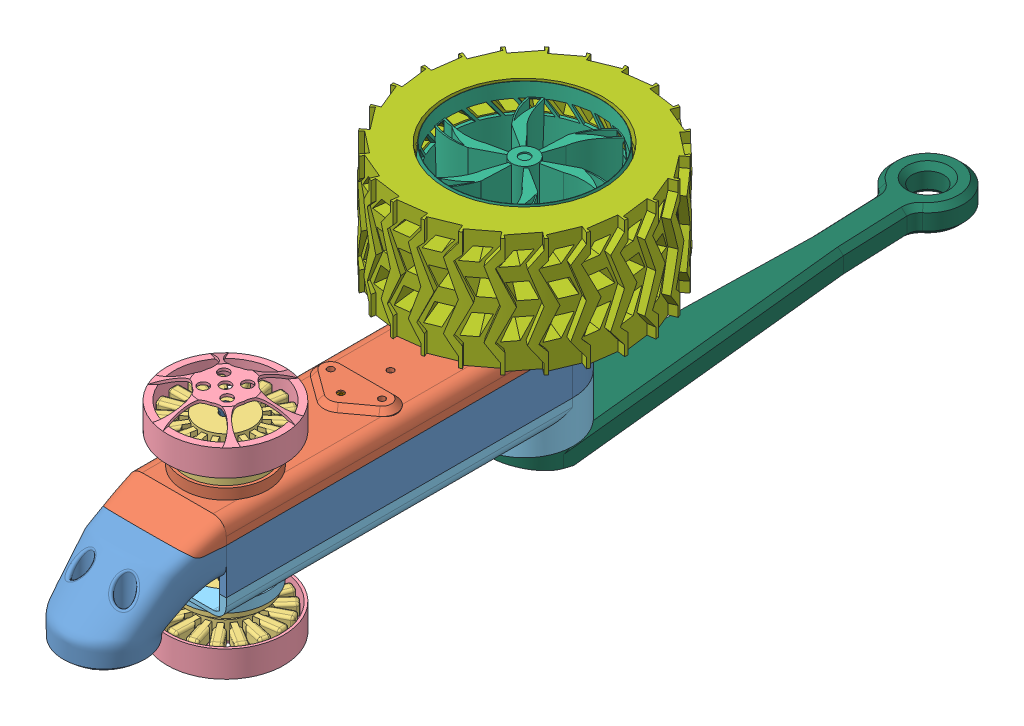
SolidWorks assembly actuator core v2, configuration Default. Lengths in mm.
Overall size (129.6 114.49 349.41).
35 component instances, 16 part files, 37 mates.
Components (placement in the parent):
- upper leg module shell base_v2-1: upper leg module shell base_v2 [Default] at (33.8696 112.35 155.1525) x (-1 0 0) z (0 0 -1) size (37.03 37.51 198.25)
- upper leg module cover_v2-1: upper leg module cover_v2 [Default] at (33.8696 118.35 148.7817) x (0 0 1) z (-1 0 0) size (170.23 17.96 37.06)
- T-motor 4004 kv300-1: T-motor 4004 kv300 [Default] at (68.2159 118.2197 199.3062) x (-0.164171 0 0.986432) z (-0.986432 0 -0.164171) size (60.94 23.74 60.94)
  - motor rotor-1: motor rotor [Default] at (14.1676 19.6303 32.4608) size (40 13.5 39.72)
  - motor stator-1: motor stator [Default] at (14.1676 19.6303 32.4608) x (0.854442 0 0.519546) z (0 1 0) size (44.35 44.35 16.24)
- upper leg module cover_v2_2-1: upper leg module cover_v2_2 [Default] at (33.8696 101.1 148.7817) x (0 0 1) z (1 0 0) size (150.55 16.02 37.05)
- T-motor 4004 kv300-2: T-motor 4004 kv300 [Default] at (54.5487 101.2303 179.1983) x (-0.977624 0 -0.21036) z (-0.21036 0 0.977624) size (60.94 23.74 60.94)
  - motor rotor-1: motor rotor [Default] at (14.1676 19.6303 32.4608) size (40 13.5 39.72)
  - motor stator-1: motor stator [Default] at (14.1676 19.6303 32.4608) x (0.854442 0 0.519546) z (0 1 0) size (44.35 44.35 16.24)
- Wheel assembly with motor-1: Wheel assembly with motor [Default] at (75.6805 196.4252 90.9747) x (-0.546944 0 0.837169) z (0 -1 0) size (125.19 125.19 45)
  - wheel-1: wheel [Default] at (25.5285 33.2647 43.0752) size (60 60 45) (hidden)
  - tyre-1: tyre [Default] at (25.5285 33.2647 65.5752) x (0 0 -1) z (0.823199 0.567753 0) size (45 90 90) (hidden)
- centre pulley-1: centre pulley [Default] at (48.6362 100.0034 142.2312) x (0.62745 0 0.778657) z (-0.778657 0 0.62745) size (30 19 30)
  - transmission pulley centre-1: transmission pulley centre [Default] at (7.726 11.8465 25.1899) size (30 6.8 30)
  - centre pulley-1: centre pulley [Default] at (7.726 25.3465 25.1899) x (0.694658 0 -0.71934) z (0 -1 0) size (8.98 9.1 19)
- motor assembly-1: motor assembly [Default] at (33.8696 146.45 207.9525) x (0.833002 0 0.55327) z (-0.55327 0 0.833002) size (16.67 33.4 16.67)
  - motor shaft-1: motor shaft [Default] x (1 0 0) z (0 -1 0) size (3.99 3.99 33.4)
  - motor pulley-1: motor pulley [Default] at (0 -20.1 0) x (1 0 0) z (0 -1 0) size (8.98 9.1 6.7)
  - encoder wheel mount-1: encoder wheel mount [Default] at (0 -28.3 0) x (-0.562764 0 0.826618) z (-0.826618 0 -0.562764) size (12 5.96 12)
- bearing 8mm x 3mm x 3mm-1: bearing 8mm x 3mm x 3mm [Default] at (33.8696 107.85 164.0525) x (-0.837169 0 -0.546944) z (0 1 0) size (7.96 7.96 3)
- bearing 8mm x 3mm x 3mm-2: bearing 8mm x 3mm x 3mm [Default] at (33.8696 105.85 164.0525) x (-0.433108 0 -0.901342) z (0 -1 0) size (7.96 7.96 3)
- centre pulley-2: centre pulley [Default] at (26.1436 113.6965 189.2423) x (1 0 0) z (0 0 -1) size (30 19 30)
  - transmission pulley centre-1: transmission pulley centre [Default] at (7.726 11.8465 25.1899) size (30 6.8 30)
  - centre pulley-1: centre pulley [Default] at (7.726 25.3465 25.1899) x (0.694658 0 -0.71934) z (0 -1 0) size (8.98 9.1 19)
- motor assembly-2: motor assembly [Default] at (33.8696 75.45 207.9525) x (-0.884301 0 -0.466918) z (-0.466918 0 0.884301) size (16.67 33.4 16.67)
  - motor shaft-1: motor shaft [Default] x (1 0 0) z (0 -1 0) size (3.99 3.99 33.4)
  - motor pulley-1: motor pulley [Default] at (0 -20.1 0) x (1 0 0) z (0 -1 0) size (8.98 9.1 6.7)
  - encoder wheel mount-1: encoder wheel mount [Default] at (0 -28.3 0) x (-0.562764 0 0.826618) z (-0.826618 0 -0.562764) size (12 5.96 12)
- bearing 32x25x4mm-1: bearing 32x25x4mm [Default] at (33.8696 125.85 94.1525) x (0.997693 0 -0.067886) z (0.067886 0 0.997693) size (32 4 32)
- bearing 32x25x4mm-2: bearing 32x25x4mm [Default] at (33.8696 87.09 94.1525) x (0.713696 0 0.700456) z (-0.700456 0 0.713696) size (32 4 32)
- lower leg-2: lower leg [Default] at (30.6462 71.09 14.2174) x (-0.040292 0 -0.999188) z (0.999188 0 -0.040292) size (187 20 27)
- Wheel assembly with motor-2: Wheel assembly with motor [Default] at (7.1635 200.4252 61.8255) x (0.999356 0 -0.035895) z (0 -1 0) size (125.19 125.19 45)
  - wheel-1: wheel [Default] at (25.5285 33.2647 43.0752) size (60 60 45) (hidden)
  - tyre-1: tyre [Default] at (25.5285 33.2647 65.5752) x (0 0 -1) z (0.823199 0.567753 0) size (45 90 90) (hidden)
- transmission pulley output-1: transmission pulley output [Default] at (33.8696 99.14 94.1525) x (-0.999188 0 0.040292) z (0.040292 0 0.999188) size (29 16.4 29)
Mates (geometry in assembly coordinates):
- Coincident1: coincident anti-aligned: plane of upper leg module shell base_v2-1 through (15.3696 118.35 115.1525) normal (0 1 0); plane of upper leg module cover_v2-1 through (33.8696 118.35 148.7817) normal (0 -1 0)
- Coincident2: coincident anti-aligned: plane of upper leg module shell base_v2-1 through (52.3737 75.9862 185.6653) normal (0 0.766044 -0.642788); plane of upper leg module cover_v2-1 through (52.4196 75.3282 184.8812) normal (0 -0.766044 0.642788)
- Coincident3: coincident aligned: plane of upper leg module shell base_v2-1 through (52.3696 106.35 115.1525) normal (1 0 0); plane of upper leg module cover_v2-1 through (52.3696 126.35 226.1517) normal (1 0 0)
- Concentric1: concentric aligned: cylinder of upper leg module cover_v2-1 through (33.8696 130.35 207.9525) axis (0 -1 0) radius 16.1235; circle of T-motor 4004 kv300-1/motor rotor-1
- Coincident4: coincident anti-aligned: plane of upper leg module cover_v2-1 through (33.8696 130.35 207.9525) normal (0 1 0); plane of T-motor 4004 kv300-1/motor rotor-1 through (33.8696 130.35 207.9525) normal (0 -1 0)
- Coincident5: coincident anti-aligned: plane of upper leg module shell base_v2-1 through (33.8696 101.1 155.1525) normal (0 -1 0); plane of upper leg module cover_v2_2-1 through (33.8696 101.1 148.7817) normal (0 1 0)
- Coincident6: coincident aligned: plane of upper leg module shell base_v2-1 through (52.3696 106.35 115.1525) normal (1 0 0); plane of upper leg module cover_v2_2-1 through (52.3696 93.1 226.1517) normal (1 0 0)
- Concentric2: concentric aligned: cylinder of upper leg module cover_v2-1 through (33.8696 130.35 207.9525) axis (0 -1 0) radius 16.1235; cylinder of upper leg module cover_v2_2-1 through (33.8696 98.1 207.9525) axis (0 -1 0) radius 12.5
- Concentric5: concentric anti-aligned: cylinder of upper leg module cover_v2_2-1 through (33.8696 89.1 207.9525) axis (0 1 0) radius 16.1235; cylinder of T-motor 4004 kv300-2/motor rotor-1 through (33.8696 86.6 207.9525) axis (0 -1 0) radius 6
- Coincident7: coincident anti-aligned: plane of upper leg module cover_v2_2-1 through (33.8696 89.1 207.9525) normal (0 -1 0); plane of T-motor 4004 kv300-2/motor rotor-1 through (33.8696 89.1 207.9525) normal (0 1 0)
- Coincident9: coincident anti-aligned: plane of upper leg module cover_v2-1 through (33.8696 132.35 94.1525) normal (0 1 0); plane of Wheel assembly with motor-1/wheel-1 through (33.8696 132.35 94.1525) normal (0 -1 0)
- Concentric7: concentric anti-aligned: cylinder of upper leg module cover_v2-1 through (33.8696 120.35 94.1525) axis (0 1 0) radius 16.4954; cylinder of Wheel assembly with motor-1/wheel-1 through (33.8696 156.35 94.1525) axis (0 -1 0) radius 9.4958
- Concentric8: concentric aligned: cylinder of upper leg module cover_v2_2-1 through (33.8696 101.1005 94.1525) axis (0 -1 0) radius 14.25; cylinder of lower leg-1 through (33.8696 81.09 94.1525) axis (0 -1 0) radius 13.5
- Coincident10: coincident anti-aligned: plane of upper leg module cover_v2_2-1 through (33.8696 85.09 94.1525) normal (0 -1 0); plane of lower leg-1 through (33.8696 85.09 94.1525) normal (0 1 0)
- Concentric9: concentric anti-aligned: circle of T-motor 4004 kv300-1/motor rotor-1; cylinder of motor assembly-1/motor shaft-1 through (33.8696 113.05 207.9525) axis (0 1 0) radius 1.995
- Distance1: distance = 4 mm anti-aligned: plane of T-motor 4004 kv300-1/motor rotor-1 through (33.8696 130.35 207.9525) normal (0 -1 0); plane of motor assembly-1/motor pulley-1 through (33.8696 126.35 207.9525) normal (0 1 0)
- Concentric10: concentric aligned: cylinder of bearing 8mm x 3mm x 3mm-1 through (33.8696 110.85 164.0525) axis (0 -1 0) radius 3.98; cylinder of upper leg module shell base_v2-1 through (33.8696 109.85 164.0525) axis (0 -1 0) radius 3.98
- Coincident12: coincident anti-aligned: plane of upper leg module shell base_v2-1 through (20.3696 107.85 115.1525) normal (0 1 0); plane of bearing 8mm x 3mm x 3mm-1 through (33.8696 107.85 164.0525) normal (0 -1 0)
- Concentric11: concentric anti-aligned: line of centre pulley-1/centre pulley-1 through (33.8696 109.05 164.0525) axis (0 1 0); cylinder of bearing 8mm x 3mm x 3mm-1 through (33.8696 110.85 164.0525) axis (0 -1 0) radius 2
- Coincident13: coincident anti-aligned: plane of centre pulley-1/centre pulley-1 through (33.8696 110.85 164.0525) normal (0 -1 0); circle of bearing 8mm x 3mm x 3mm-1
- Concentric12: concentric aligned: cylinder of upper leg module shell base_v2-1 through (33.8696 104.85 164.0525) axis (0 1 0) radius 3.98; cylinder of bearing 8mm x 3mm x 3mm-2 through (33.8696 102.85 164.0525) axis (0 1 0) radius 2
- Coincident14: coincident anti-aligned: plane of upper leg module shell base_v2-1 through (33.8696 105.85 164.0525) normal (0 -1 0); plane of bearing 8mm x 3mm x 3mm-2 through (33.8696 105.85 164.0525) normal (0 1 0)
- Coincident15: coincident anti-aligned: plane of bearing 8mm x 3mm x 3mm-2 through (33.8696 102.85 164.0525) normal (0 -1 0); plane of centre pulley-2/centre pulley-1 through (33.8696 102.85 164.0525) normal (0 1 0)
- Concentric13: concentric anti-aligned: cylinder of bearing 8mm x 3mm x 3mm-2 through (33.8696 102.85 164.0525) axis (0 1 0) radius 3.98; cylinder of centre pulley-2/transmission pulley centre-1 through (33.8696 102.35 164.0525) axis (0 -1 0) radius 15
- Concentric14: concentric anti-aligned: circle of T-motor 4004 kv300-2/motor rotor-1; cylinder of motor assembly-2/motor shaft-1 through (33.8696 108.85 207.9525) axis (0 -1 0) radius 1.995
- Concentric15: concentric anti-aligned: cylinder of upper leg module cover_v2-1 through (33.8696 120.35 94.1525) axis (0 1 0) radius 16.4954; cylinder of bearing 32x25x4mm-1 through (33.8696 129.85 94.1525) axis (0 -1 0) radius 12.5
- Distance3: distance = 2.5 mm aligned: plane of bearing 32x25x4mm-1 through (33.8696 129.85 94.1525) normal (0 1 0); plane of upper leg module cover_v2-1 through (33.8696 132.35 94.1525) normal (0 1 0)
- Coincident19: coincident aligned: plane of centre pulley-2/transmission pulley centre-1 through (33.8696 95.55 164.0525) normal (0 -1 0); plane of motor assembly-2/motor pulley-1 through (33.8696 95.55 207.9525) normal (0 -1 0)
- Concentric16: concentric anti-aligned: cylinder of upper leg module cover_v2_2-1 through (33.8696 87.09 94.1525) axis (0 1 0) radius 16.5; cylinder of bearing 32x25x4mm-2 through (33.8696 91.09 94.1525) axis (0 -1 0) radius 12.5
- Coincident23: coincident anti-aligned: plane of upper leg module cover_v2_2-1 through (33.8696 87.09 94.1525) normal (0 1 0); plane of bearing 32x25x4mm-2 through (33.8696 87.09 94.1525) normal (0 -1 0)
- Concentric17: concentric anti-aligned: cylinder of bearing 32x25x4mm-1 through (33.8696 129.85 94.1525) axis (0 -1 0) radius 12.5; cone of Wheel assembly with motor-2/wheel-1 through (33.8696 140.35 94.1525) axis (0 1 0)
- Distance4: distance = 2.5 mm anti-aligned: plane of Wheel assembly with motor-2/tyre-1 through (33.8696 134.85 94.1525) normal (0 -1 0); plane of upper leg module cover_v2-1 through (33.8696 132.35 94.1525) normal (0 1 0)
- Concentric18: concentric anti-aligned: cylinder of bearing 32x25x4mm-2 through (33.8696 91.09 94.1525) axis (0 -1 0) radius 12.5; cylinder of transmission pulley output-1 through (33.8696 87.09 94.1525) axis (0 1 0) radius 12.575
- Coincident25: coincident aligned: plane of bearing 32x25x4mm-2 through (33.8696 87.09 94.1525) normal (0 -1 0); plane of transmission pulley output-1 through (33.8696 87.09 94.1525) normal (0 -1 0)
- Coincident26: coincident anti-aligned: plane of lower leg-2 through (37.7294 91.09 103.0041) normal (0.040292 0 0.999188); plane of transmission pulley output-1 through (29.2363 103.49 103.3466) normal (-0.040292 0 -0.999188)
- Coincident27: coincident anti-aligned: plane of lower leg-2 through (39.1677 91.09 101.4449) normal (0.999188 0 -0.040292); plane of transmission pulley output-1 through (39.2282 103.49 102.9437) normal (-0.999188 0 0.040292)
- Coincident28: coincident anti-aligned: plane of upper leg module cover_v2_2-1 through (33.8696 85.09 94.1525) normal (0 -1 0); plane of lower leg-2 through (33.8696 85.09 94.1525) normal (0 1 0)
